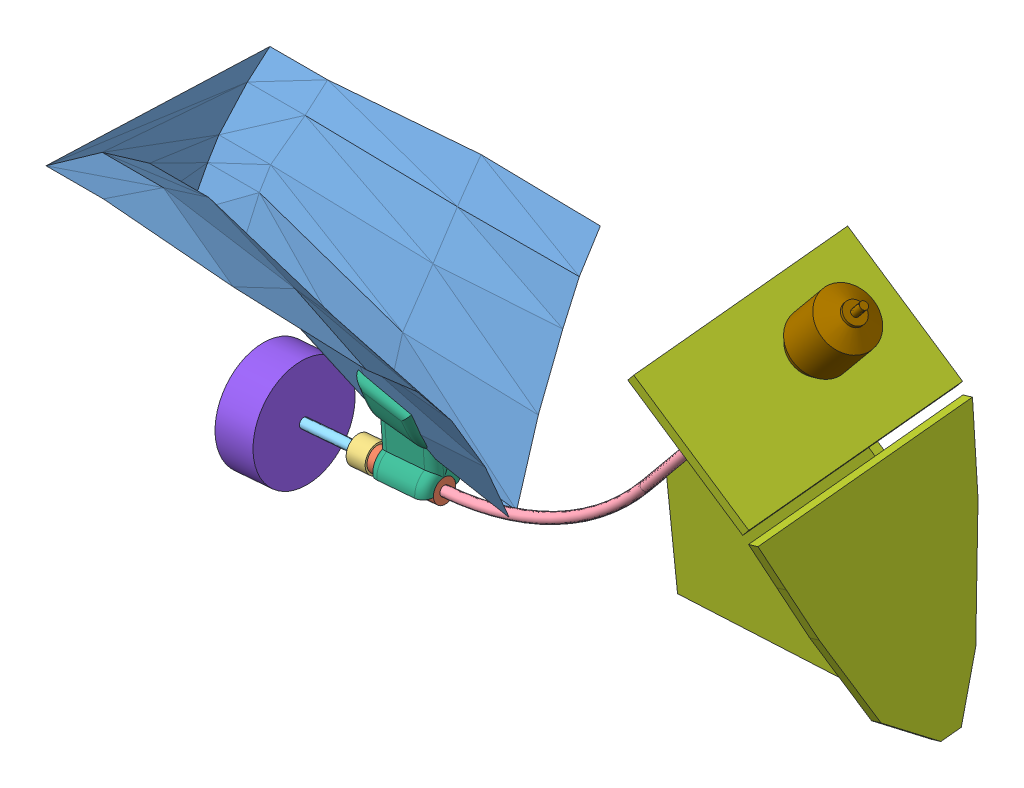
SolidWorks assembly Assem3, configuration Default. Lengths in mm.
Overall size (506.76 316.36 188.08).
10 component instances, 9 part files, 7 mates.
Components (placement in the parent):
- boat hull measured-1: boat hull measured [Default] at (-155.8966 135.4276 -58.7533) size (229.1 149.1 174.75)
- shaft assembly-1: shaft assembly [Default] at (-34.2878 -73.4998 24.2255) x (-0.997594 -0.067697 0.014968) z (-0.015155 0.002245 -0.999883) size (347.45 164.02 40.93)
  - hull_tube_9_21_2016-1: hull_tube_9_21_2016 [Default] at (-44.6237 -26.3034 16.088) x (1 0 0) z (0 -0.279591 0.960119) size (55.88 15.24 15.24)
  - cap-1: cap [Default] at (-0.1737 -26.3034 16.088) size (12.7 17.78 17.78)
  - tube-1: tube [Default] at (-19.2237 -26.3034 16.088) size (253.47 157.75 6.35)
  - shaft prop coupling-1: shaft prop coupling [Default] at (-19.2237 -26.3034 16.088) x (1 0 0) z (0 -0.833873 0.551956) size (93.98 9.53 9.53)
  - Brace_boat_conform-1: Brace_boat_conform [Default<As Machined>] at (-336.7237 141.0036 -319.5521) x (0 0 1) z (-1 0 0) size (40.93 63.37 39.38)
- plywood frame-1: plywood frame [Default] at (69.6866 -46.01 12.5059) x (-0.996052 -0.06854 0.056421) z (-0.059145 0.038385 -0.997511) size (342.16 220.27 154.76)
- Octura 1270 Plastic standin-1: Octura 1270 Plastic standin [Default] at (-107.3284 -104.7675 9.1724) x (-0.041605 0.757222 0.651831) z (0.997594 0.067697 -0.014968) size (70 70 25.4)
- Motor_8_29_16-2: Motor_8_29_16 [Default] at (268.4167 121.4963 3.9854) x (0.634515 0.77287 -0.007882) z (0.007882 0.003727 0.999962) size (74.63 37.64 37.64)
Mates (geometry in assembly coordinates):
- Coincident4: coincident anti-aligned: plane of boat hull measured-1 through (-166.5264 71.0827 70.5618) normal (-0.073395 -0.444279 0.892877); plane of ? through (-29.1257 -54.2484 19.4936) normal (0.073395 0.444279 -0.892877)
- Tangent2: tangent anti-aligned: cylinder of shaft assembly-1/tube-1 through (146.0871 -27.5071 5.505) axis (0.634515 0.77287 -0.007882) radius 3.175; plane of plywood frame-1 through (255.4777 101.0952 0.7847) normal (-0.770644 0.633402 0.070067)
- Tangent3: tangent aligned: cylinder of shaft assembly-1/tube-1 through (146.0871 -27.5071 5.505) axis (0.634515 0.77287 -0.007882) radius 3.175; plane of plywood frame-1 through (69.6866 -46.01 12.5059) normal (0.059145 -0.038385 0.997511)
- Concentric1: concentric anti-aligned: cylinder of shaft assembly-1/shaft prop coupling-1 through (-13.5746 -98.4053 7.7657) axis (0.997594 0.067697 -0.014968) radius 2.3813; cylinder of Octura 1270 Plastic standin-1 through (-81.9895 -103.048 8.7923) axis (-0.997594 -0.067697 0.014968) radius 2.3813
- Coincident6: coincident aligned: plane of shaft assembly-1/shaft prop coupling-1 through (-107.4474 -103.4517 7.1913) normal (-0.997594 -0.067697 0.014968); plane of Octura 1270 Plastic standin-1 through (-107.3284 -104.7675 9.1724) normal (-0.997594 -0.067697 0.014968)
- Coincident7: coincident anti-aligned: plane of plywood frame-1 through (220.7157 137.9508 10.6298) normal (0.634515 0.77287 -0.007882); plane of Motor_8_29_16-2 through (245.6362 117.4257 4.1802) normal (-0.634515 -0.77287 0.007882)
- Concentric2: concentric anti-aligned: cylinder of shaft assembly-1/tube-1 through (146.0871 -27.5071 5.505) axis (0.634515 0.77287 -0.007882) radius 3.175; cylinder of Motor_8_29_16-2 through (268.4167 121.4963 3.9854) axis (-0.634515 -0.77287 0.007882) radius 2.5019
